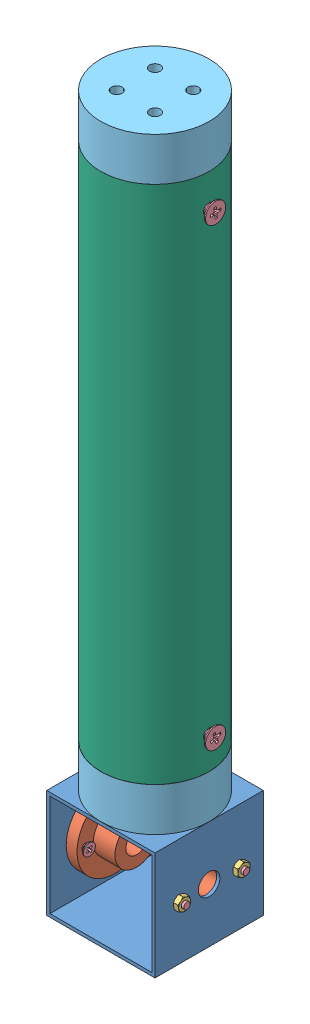
SolidWorks assembly Elo1-2-Assembly, configuration Valor predeterminado. Lengths in mm.
Overall size (57.04 330 50).
23 component instances, 6 part files, 21 mates.
Components (placement in the parent):
- Caixa Alumínio-1: Caixa Alumínio [Valor predeterminado] at (9.4209 -0.6877 57.0373) size (57.04 50 50)
  - Caixa Aluminio 1-1: Caixa Aluminio 1 [Valor predeterminado] at (-10.4524 1.2722 25) size (50 50 50)
  - Bucha 10 mm-1: Bucha 10 mm [Valor predeterminado] at (-33.9524 1.2722 50) x (0 -1 0) z (0 0 1) size (35 15 35)
  - Bucha 10 mm-2: Bucha 10 mm [Valor predeterminado] at (13.0476 1.2722 50) x (0 1 0) z (0 0 1) size (35 15 35)
  - hex nut style 1 gradeab_iso-1: hex nut style 1 gradeab_iso [ISO - 4032 - M3 - D - N] at (14.5476 1.2722 36.25) x (0 -0.866025 0.5) z (-1 0 0) size (5.5 6.35 2.4)
  - countersunk flat head cross recess screw_iso-1: countersunk flat head cross recess screw_iso [ISO 7046-1 - M3 x 12 - Z - 12N] at (6.0663 1.2722 36.25) x (1 0 0) z (0 -0.400835 0.91615) size (12 5.5 5.5)
  - hex nut style 1 gradeab_iso-2: hex nut style 1 gradeab_iso [ISO - 4032 - M3 - D - N] at (-35.4524 1.2722 36.25) x (0 0.249017 -0.968499) z (1 0 0) size (5.5 6.35 2.4)
  - countersunk flat head cross recess screw_iso-2: countersunk flat head cross recess screw_iso [ISO 7046-1 - M3 x 12 - Z - 12N] at (-26.971 1.2722 36.25) x (-1 0 0) z (0 -0.725577 0.688141) size (12 5.5 5.5)
  - hex nut style 1 gradeab_iso-3: hex nut style 1 gradeab_iso [ISO - 4032 - M3 - D - N] at (14.5476 1.2722 63.75) x (0 -0.934192 0.356771) z (-1 0 0) size (5.5 6.35 2.4)
  - countersunk flat head cross recess screw_iso-3: countersunk flat head cross recess screw_iso [ISO 7046-1 - M3 x 12 - Z - 12N] at (6.0663 1.2722 63.75) x (1 0 0) z (0 -0.540657 0.841243) size (12 5.5 5.5)
  - countersunk flat head cross recess screw_iso-4: countersunk flat head cross recess screw_iso [ISO 7046-1 - M3 x 12 - Z - 12N] at (-26.971 1.2722 63.75) x (-1 0 0) z (0 -0.594897 0.803802) size (12 5.5 5.5)
  - hex nut style 1 gradeab_iso-4: hex nut style 1 gradeab_iso [ISO - 4032 - M3 - D - N] at (-35.4524 1.2722 63.75) x (0 0.146862 -0.989157) z (1 0 0) size (5.5 6.35 2.4)
- Conector Nylon-1: Conector Nylon [Valor predeterminado] at (-1.0315 45.5845 107.0373) x (0 0 -1) z (1 0 0) size (50 50 50)
- Conector PVC 1-2-1: Conector PVC 1-2 [Valor predeterminado] at (-1.0315 45.5845 107.0373) x (0 0 1) z (-1 0 0) size (50 240 50)
- Conector Nylon-2: Conector Nylon [Valor predeterminado] at (-1.0315 285.5845 107.0373) x (0 0 -1) z (-1 0 0) size (50 50 50)
- countersunk flat head cross recess screw_iso-1: countersunk flat head cross recess screw_iso [ISO 7046-1 - M5 x 16 - Z - 16N] at (7.8074 20.846 98.1984) x (0 1 0) z (-0.754513 0 -0.656285) size (16 9.3 9.3)
- countersunk flat head cross recess screw_iso-2: countersunk flat head cross recess screw_iso [ISO 7046-1 - M5 x 16 - Z - 16N] at (7.8074 20.846 115.8761) x (0 1 0) z (0.358811 0 0.93341) size (16 9.3 9.3)
- countersunk flat head cross recess screw_iso-3: countersunk flat head cross recess screw_iso [ISO 7046-1 - M5 x 16 - Z - 16N] at (-9.8703 20.846 98.1984) x (0 1 0) z (0.415617 0 0.90954) size (16 9.3 9.3)
- countersunk flat head cross recess screw_iso-4: countersunk flat head cross recess screw_iso [ISO 7046-1 - M5 x 16 - Z - 16N] at (-9.8703 20.846 115.8761) x (0 1 0) z (-0.840032 0 -0.542537) size (16 9.3 9.3)
- countersunk flat head cross recess screw_iso-5: countersunk flat head cross recess screw_iso [ISO 7046-1 - M5 x 10 - Z - 10N] at (-29.0315 270.5845 107.0373) x (1 0 0) z (0 -0.633547 0.773704) size (10 9.3 9.3)
- countersunk flat head cross recess screw_iso-6: countersunk flat head cross recess screw_iso [ISO 7046-1 - M5 x 10 - Z - 10N] at (26.9685 270.5845 107.0373) x (-1 0 0) z (0 0.112006 -0.993708) size (10 9.3 9.3)
- countersunk flat head cross recess screw_iso-7: countersunk flat head cross recess screw_iso [ISO 7046-1 - M5 x 10 - Z - 10N] at (-29.0315 60.5845 107.0373) x (1 0 0) z (0 -0.562007 -0.827132) size (10 9.3 9.3)
- countersunk flat head cross recess screw_iso-8: countersunk flat head cross recess screw_iso [ISO 7046-1 - M5 x 10 - Z - 10N] at (26.9685 60.5845 107.0373) x (-1 0 0) z (0 0.949956 0.312384) size (10 9.3 9.3)
Mates (geometry in assembly coordinates):
- Coincident3: coincident: plane of Caixa Alumínio-1/Caixa Aluminio 1-1 through (23.9685 25.5845 132.0373) normal (0 1 0); plane of Conector Nylon-1 through (-1.0315 25.5845 107.0373) normal (0 -1 0)
- Coincident4: coincident: circle of Caixa Alumínio-1/Caixa Aluminio 1-1; circle of countersunk flat head cross recess screw_iso-4
- Coincident5: coincident: circle of Caixa Alumínio-1/Caixa Aluminio 1-1; circle of countersunk flat head cross recess screw_iso-2
- Coincident6: coincident: circle of Caixa Alumínio-1/Caixa Aluminio 1-1; circle of countersunk flat head cross recess screw_iso-3
- Coincident7: coincident: circle of Caixa Alumínio-1/Caixa Aluminio 1-1; circle of countersunk flat head cross recess screw_iso-1
- Coincident8: coincident: circle of Caixa Alumínio-1/Caixa Aluminio 1-1; circle of Conector Nylon-1
- Coincident9: coincident: circle of Caixa Alumínio-1/Caixa Aluminio 1-1; circle of Conector Nylon-1
- Concentric3: concentric: cylinder of Conector Nylon-1 through (24.7685 60.5845 107.0373) axis (1 0 0) radius 2.1; cylinder of Conector PVC 1-2-1 through (23.9685 60.5845 107.0373) axis (-1 0 0) radius 2.5
- Concentric4: concentric: cylinder of Conector Nylon-1 through (-1.0315 75.5855 107.0373) axis (0 -1 0) radius 25; circle of Conector PVC 1-2-1
- Concentric5: concentric: cylinder of Conector PVC 1-2-1 through (23.9685 270.5845 107.0373) axis (-1 0 0) radius 2.5; cylinder of Conector Nylon-2 through (-26.8315 270.5845 107.0373) axis (-1 0 0) radius 2.1
- Concentric6: concentric: cylinder of Conector PVC 1-2-1 through (-1.0315 285.5845 107.0373) axis (0 -1 0) radius 22; cylinder of Conector Nylon-2 through (-1.0315 255.5845 107.0373) axis (0 1 0) radius 22
- Coincident10: coincident: plane of countersunk flat head cross recess screw_iso-6 through (26.9685 270.5845 107.0373) normal (1 0 0); plane of countersunk flat head cross recess screw_iso-8 through (26.9685 60.5845 107.0373) normal (1 0 0)
- Coincident11: coincident: plane of countersunk flat head cross recess screw_iso-5 through (-29.0315 270.5845 107.0373) normal (-1 0 0); plane of countersunk flat head cross recess screw_iso-7 through (-29.0315 60.5845 107.0373) normal (-1 0 0)
- Concentric7: concentric: cylinder of Conector PVC 1-2-1 through (23.9685 60.5845 107.0373) axis (-1 0 0) radius 2.5; circle of countersunk flat head cross recess screw_iso-8
- Concentric8: concentric: cylinder of Conector PVC 1-2-1 through (23.9685 270.5845 107.0373) axis (-1 0 0) radius 2.5; circle of countersunk flat head cross recess screw_iso-5
- Concentric9: concentric: cylinder of Conector PVC 1-2-1 through (23.9685 270.5845 107.0373) axis (-1 0 0) radius 2.5; circle of countersunk flat head cross recess screw_iso-6
- Concentric10: concentric: cylinder of Conector PVC 1-2-1 through (23.9685 60.5845 107.0373) axis (-1 0 0) radius 2.5; circle of countersunk flat head cross recess screw_iso-7
- Distance1: distance = 3 mm: plane of countersunk flat head cross recess screw_iso-8 through (26.9685 60.5845 107.0373) normal (1 0 0); plane of Caixa Alumínio-1/Caixa Aluminio 1-1 through (23.9685 -24.4155 132.0373) normal (1 0 0)
- Distance2: distance = 3 mm: plane of countersunk flat head cross recess screw_iso-7 through (-29.0315 60.5845 107.0373) normal (-1 0 0); plane of Caixa Alumínio-1/Caixa Aluminio 1-1 through (-26.0315 -24.4155 132.0373) normal (-1 0 0)
- Coincident19: coincident: plane of countersunk flat head cross recess screw_iso-6 through (26.9685 270.5845 107.0373) normal (1 0 0); plane of countersunk flat head cross recess screw_iso-8 through (26.9685 60.5845 107.0373) normal (1 0 0)
- Coincident20: coincident: plane of countersunk flat head cross recess screw_iso-5 through (-29.0315 270.5845 107.0373) normal (-1 0 0); plane of countersunk flat head cross recess screw_iso-7 through (-29.0315 60.5845 107.0373) normal (-1 0 0)
